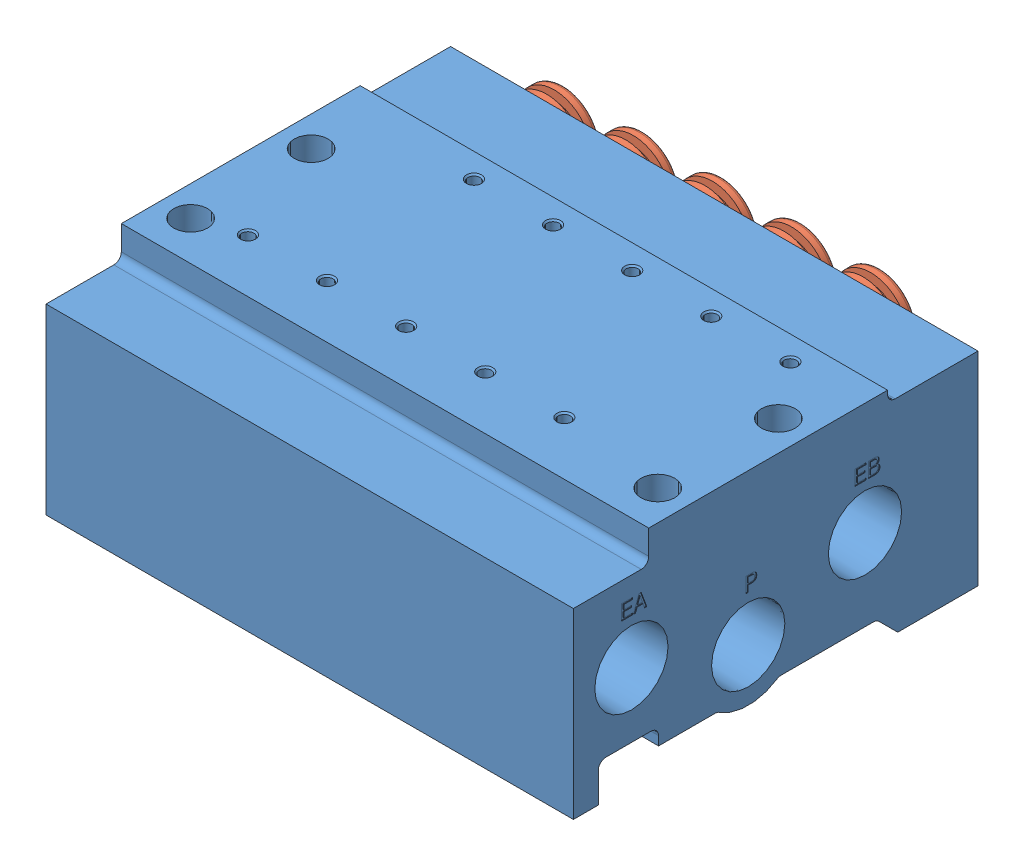
SolidWorks assembly 5 Station Manifold 217-2953, configuration Default. Lengths in mm.
Overall size (70 28.5 58.2).
11 component instances, 2 part files, 0 mates.
Components (placement in the parent):
- Copy of 217-2953-001 Rev1_41^5 Station Manifold 217-2953-1: Copy of 217-2953-001 Rev1_41^5 Station Manifold 217-2953 [Default] at origin size (70 28.5 53.7) (virtual)
- Copy of 217-2953-002 Rev1_1000-50A-N7^5 Station Manifold 217-2953-1: Copy of 217-2953-002 Rev1_1000-50A-N7^5 Station Manifold 217-2953 [Default] at (-10.5 -22 -15.65) x (1 0 0) z (0 0 -1) size (10 10 15.7) (virtual)
- Copy of 217-2953-002 Rev1_1000-50A-N7^5 Station Manifold 217-2953-2: Copy of 217-2953-002 Rev1_1000-50A-N7^5 Station Manifold 217-2953 [Default] at (-17.5 -7.8 -15.65) x (1 0 0) z (0 0 -1) size (10 10 15.7) (virtual)
- Copy of 217-2953-002 Rev1_1000-50A-N7^5 Station Manifold 217-2953-3: Copy of 217-2953-002 Rev1_1000-50A-N7^5 Station Manifold 217-2953 [Default] at (-21 -22 -15.65) x (1 0 0) z (0 0 -1) size (10 10 15.7) (virtual)
- Copy of 217-2953-002 Rev1_1000-50A-N7^5 Station Manifold 217-2953-4: Copy of 217-2953-002 Rev1_1000-50A-N7^5 Station Manifold 217-2953 [Default] at (-28 -7.8 -15.65) x (1 0 0) z (0 0 -1) size (10 10 15.7) (virtual)
- Copy of 217-2953-002 Rev1_1000-50A-N7^5 Station Manifold 217-2953-5: Copy of 217-2953-002 Rev1_1000-50A-N7^5 Station Manifold 217-2953 [Default] at (-31.5 -22 -15.65) x (1 0 0) z (0 0 -1) size (10 10 15.7) (virtual)
- Copy of 217-2953-002 Rev1_1000-50A-N7^5 Station Manifold 217-2953-6: Copy of 217-2953-002 Rev1_1000-50A-N7^5 Station Manifold 217-2953 [Default] at (-38.5 -7.8 -15.65) x (1 0 0) z (0 0 -1) size (10 10 15.7) (virtual)
- Copy of 217-2953-002 Rev1_1000-50A-N7^5 Station Manifold 217-2953-7: Copy of 217-2953-002 Rev1_1000-50A-N7^5 Station Manifold 217-2953 [Default] at (-42 -22 -15.65) x (1 0 0) z (0 0 -1) size (10 10 15.7) (virtual)
- Copy of 217-2953-002 Rev1_1000-50A-N7^5 Station Manifold 217-2953-8: Copy of 217-2953-002 Rev1_1000-50A-N7^5 Station Manifold 217-2953 [Default] at (-52.5 -22 -15.65) x (1 0 0) z (0 0 -1) size (10 10 15.7) (virtual)
- Copy of 217-2953-002 Rev1_1000-50A-N7^5 Station Manifold 217-2953-9: Copy of 217-2953-002 Rev1_1000-50A-N7^5 Station Manifold 217-2953 [Default] at (-49 -7.8 -15.65) x (1 0 0) z (0 0 -1) size (10 10 15.7) (virtual)
- Copy of 217-2953-002 Rev1_1000-50A-N7^5 Station Manifold 217-2953-10: Copy of 217-2953-002 Rev1_1000-50A-N7^5 Station Manifold 217-2953 [Default] at (-59.5 -7.8 -15.65) x (1 0 0) z (0 0 -1) size (10 10 15.7) (virtual)
